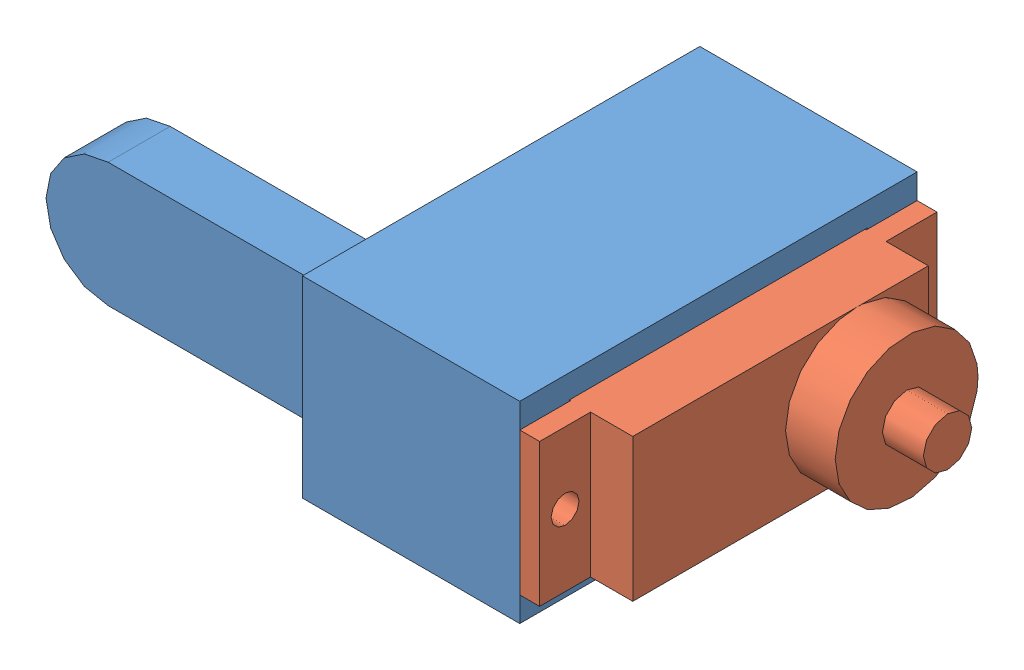
SolidWorks assembly Wrist, configuration Default. Lengths in mm.
Overall size (53.3 15.5 32).
2 component instances, 2 part files, 3 mates.
Components (placement in the parent):
- ArmLink2-1: ArmLink2 [Default] at origin size (41 15.5 32)
- SG90MicroServo-1: SG90MicroServo [Default] at (21 0 -8.15) x (0 0 -1) z (1 0 0) size (32 11.5 27.3)
Mates (geometry in assembly coordinates):
- Concentric1: concentric anti-aligned: line of ArmLink2-1 through (-6.295 0 -14.3) axis (1 0 0); cylinder of SG90MicroServo-1 through (81.1154 0 -14.3) axis (-1 0 0) radius 1.95
- Parallel1: parallel anti-aligned: plane of ArmLink2-1 through (0 0 0) normal (0 0 -1); plane of SG90MicroServo-1 through (41 -5.75 3.75) normal (0 0 1)
- Distance1: distance = 45 mm: plane of assembly through (0 0 0) normal (1 0 0); plane of assembly; plane of SG90MicroServo-1 through (45 0 -14.3) normal (1 0 0)
